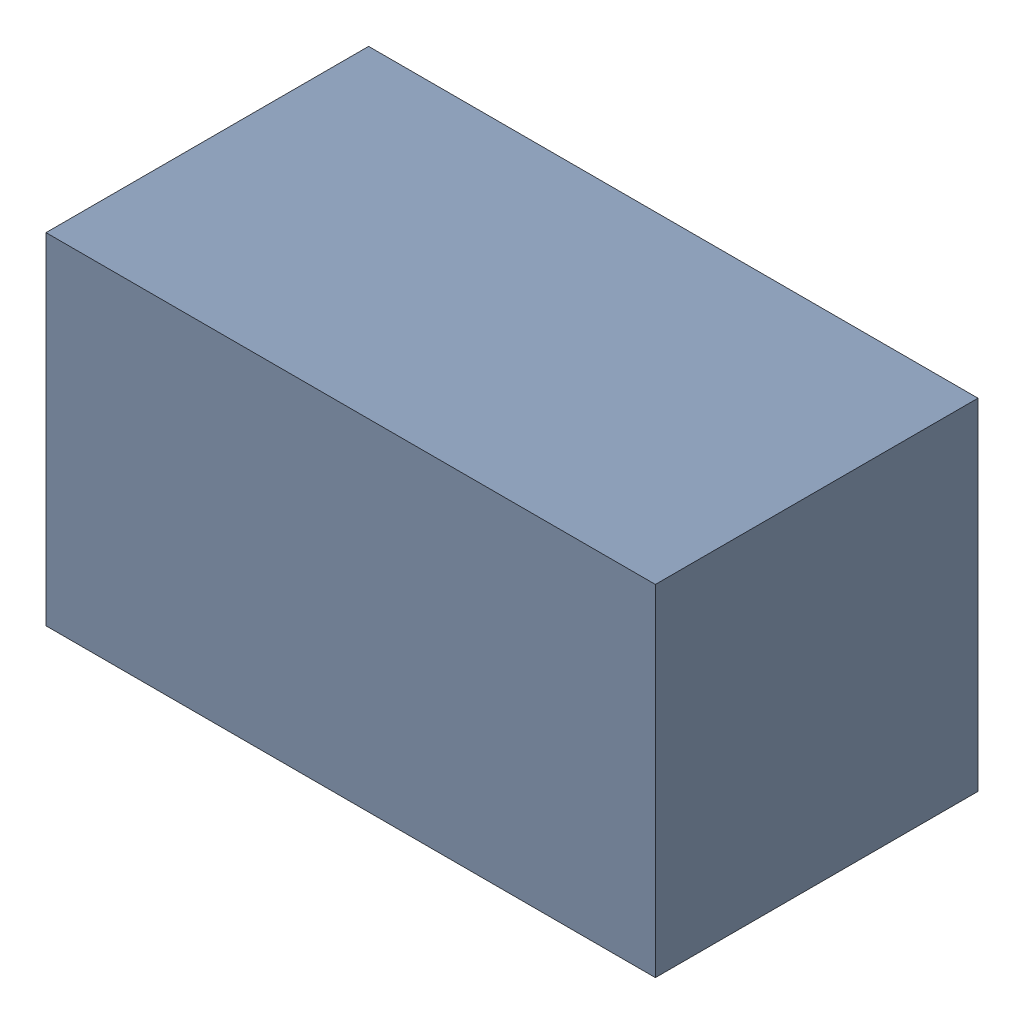
SolidWorks assembly R1, configuration Default. Lengths in mm.
Overall size (1.7 0.95 0.9).
2 component instances, 1 part files, 0 mates.
Components (placement in the parent):
- 580483600-1: 580483600 [Default] at (210.439 108.839 0) size (1.7 0.95 0.9)
  - Extruded_3-1: Extruded_3 [Default] at origin size (1.7 0.95 0.9)
